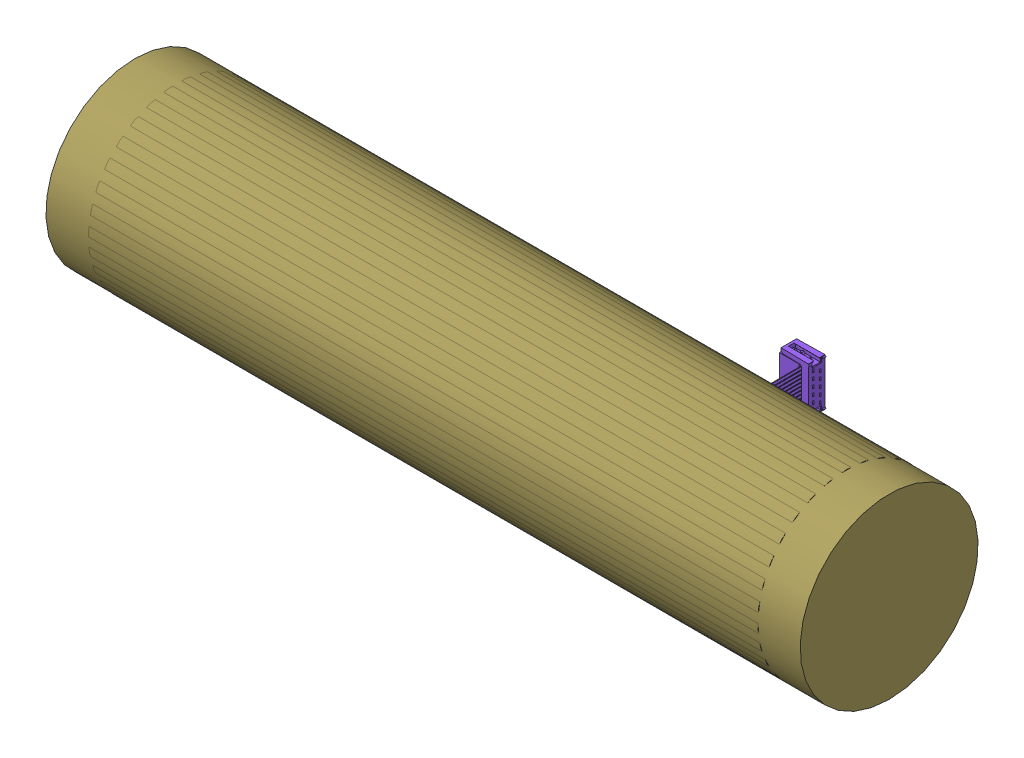
SolidWorks assembly 装配体1, configuration Default. Lengths in mm.
Overall size (275.5 65 89.7).
15 component instances, 12 part files, 4 mates.
Components (placement in the parent):
- ArmMotorCAD-1: ArmMotorCAD [Default] at (-123.3739 14.9228 52.9523) size (206.2 42 78.2)
  - ArmMotorCAD.stp-1: ArmMotorCAD.stp [Default] at origin size (206.2 42 78.2)
    - 0.stp-1: 0.stp [Default] at origin size (20 4 4)
    - 0-0.stp-1: 0-0.stp [默认] at origin size (30.5 12 12)
    - 0-1.stp-1: 0-1.stp [默认] at origin size (7 14.3 16)
    - 0-2.stp-1: 0-2.stp [默认] at origin size (8 28 28)
    - 0-3.stp-1: 0-3.stp [Default] at origin size (61.95 42 42)
    - 0-4.stp-1: 0-4.stp [Default] at origin size (12.4 42 42)
    - 0-5.stp-1: 0-5.stp [Default] at origin size (13.5 42 42)
    - 0-6.stp-1: 0-6.stp [Default] at origin size (20.95 30 72.2)
    - 0-7.stp-1: 0-7.stp [Default] at origin size (2.3 29.7 30)
    - 0-8.stp-1: 0-8.stp [Default] at origin size (3.5 34.51 34.68)
    - 0-9.stp-1: 0-9.stp [Default] at origin size (6.99 3.52 30.53)
- top-1: top [默认] at (-137.3739 14.9228 30.4523) x (0 0 1) z (0 1 0) size (65 260 65)
- top-2: top [默认] at (-152.8739 14.9228 75.4523) x (0 0 -1) z (0 -1 0) size (65 260 65)
Mates (geometry in assembly coordinates):
- 重合1: coincident anti-aligned: plane of ArmMotorCAD-1/ArmMotorCAD.stp-1/0-1.stp-1 through (-127.3739 17.9598 52.7421) normal (-1 0 0); plane of top-1 through (-127.3739 14.9228 30.4523) normal (1 0 0)
- 同心1: concentric anti-aligned: circle of ArmMotorCAD-1/ArmMotorCAD.stp-1/0-0.stp-1; circle of top-1
- 重合2: coincident aligned: plane of ArmMotorCAD-1/ArmMotorCAD.stp-1/0-0.stp-1 through (-152.8739 14.9228 52.9523) normal (-1 0 0); plane of top-2 through (-152.8739 14.9228 75.4523) normal (-1 0 0)
- 同心2: concentric aligned: circle of ArmMotorCAD-1/ArmMotorCAD.stp-1/0-0.stp-1; circle of top-2
